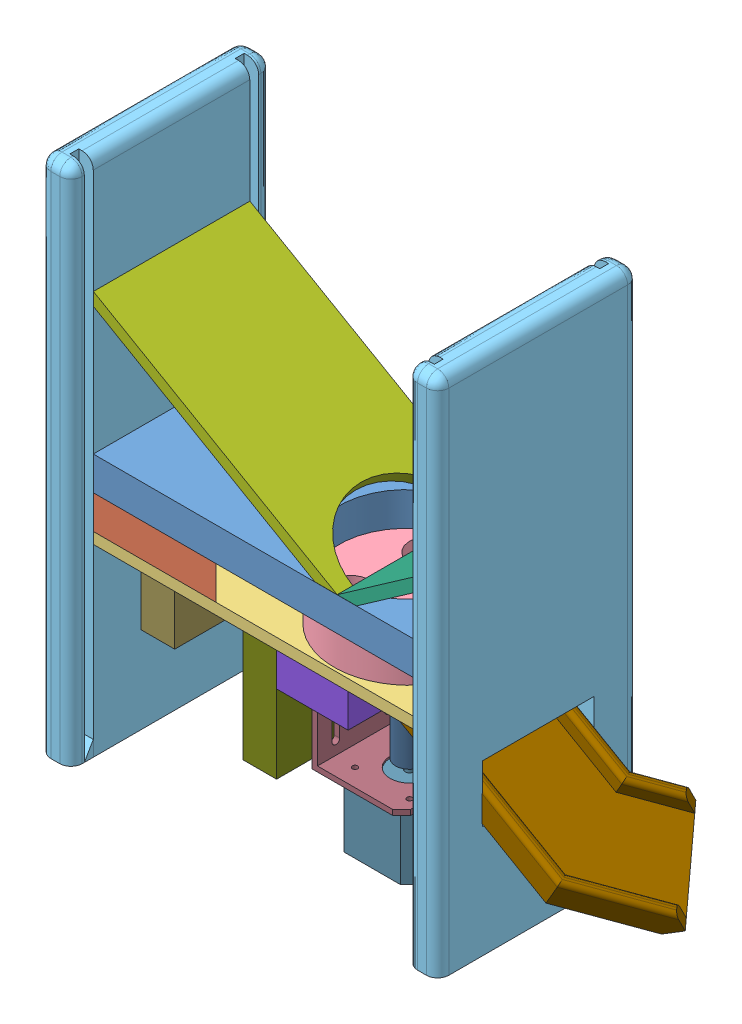
SolidWorks assembly MAIN, configuration Default. Lengths in mm.
Overall size (310.97 295.28 114.36).
20 component instances, 18 part files, 56 mates.
Components (placement in the parent):
- CenterDrop-1: CenterDrop [Default] at (73.1589 98.988 145.4321) size (190.5 19.05 88.9)
- Spacer-1: Spacer [Default] at (12.8339 79.938 145.4321) x (1 0 0) z (0 -1 0) size (69.85 88.9 19.05)
- ShaftPlate-1: ShaftPlate [Default] at (73.1589 67.238 145.4321) x (-1 0 0) z (0 -1 0) size (190.5 88.9 6.35)
- Indexer-1: Indexer [Default] at (113.1639 79.938 145.4321) x (0.075484 0 -0.997147) z (0 -1 0) size (85.72 85.72 19.05)
- SidePanel-1: SidePanel [Right] at (-30.9811 106.9255 145.4321) x (0 0 -1) z (1 0 0) size (114.3 295.28 17.78)
- SidePanel-2: SidePanel [Left] at (177.2989 106.9255 145.3686) x (0 0 1) z (-1 0 0) size (114.3 295.28 17.78)
- SlidePanel-1: SlidePanel [Default] at (73.1589 108.513 192.3586) size (207.01 292.1 5.08) (hidden)
- SmallAngle-1: SmallAngle [Default] at (144.222 124.1232 145.3686) x (0 0 -1) z (0.819152 0.573576 0) size (88.9 10.92 68.6)
- BigAngle-2: BigAngle [Default] at (53.2465 141.3043 145.3686) x (0 0 1) z (-0.866025 0.5 0) size (88.9 6.35 159.91)
- SlidePanel-2: SlidePanel [Default] at (73.1589 108.513 98.3786) x (-1 0 0) z (0 0 -1) size (207.01 292.1 5.08) (hidden)
- MotorBlock-1: MotorBlock [Default] at (102.3689 54.538 189.8821) size (40.64 19.05 88.9)
- Ramp-3: Ramp [Default] at (174.5346 34.7708 113.6821) x (-0.866025 0.5 0) z (0 0 -1) size (154.98 15.24 85.58)
- Shaft_extender-1: Shaft_extender [Default] at (113.1639 4.373 145.4321) x (0.406333 0 -0.913725) z (0.913725 0 0.406333) size (15.88 76.2 15.88)
- button-1: button [Default] at (-45.6794 41.838 145.4321) x (0 -0.933959 -0.357381) z (1 0 0) size (15.88 15.88 31.75)
- button_block-1: button_block [Default] at (-4.4044 16.565 145.4321) size (19.05 47.5 50.8)
- motor_bracket-1: motor_bracket [Default] at (113.1639 -3.247 145.4321) x (0 0 -1) z (1 0 0) size (51 48.26 51)
- motor-1: motor [Default] at (113.1639 -39.405 145.4321) x (0 0 -1) z (1 0 0) size (42.3 60.16 42.3)
- ramp_support-1: ramp_support [Default] at (166.8214 15.5913 151.7821) x (-1 0 0) z (0 0 -1) size (36.17 58.07 12.7)
- motor_block2-1: motor_block2 [Default] at (72.5239 0.563 145.4321) size (19.05 63.5 88.9)
- food_brush-1: food_brush [Default] at (116.3928 100.9412 146.1927) x (0 0 1) z (-1 0 0) size (63.5 12.7 0.38)
Mates (geometry in assembly coordinates):
- Coincident1: coincident: plane of CenterDrop-1 through (73.1589 89.463 145.4321) normal (0 -1 0); plane of Spacer-1 through (12.8339 89.463 145.4321) normal (0 1 0)
- Coincident2: coincident: plane of CenterDrop-1 through (-22.0911 108.513 100.9821) normal (-1 0 0); plane of Spacer-1 through (-22.0911 70.413 145.4321) normal (-1 0 0)
- Coincident3: coincident: plane of CenterDrop-1 through (-22.0911 108.513 100.9821) normal (0 0 -1); plane of Spacer-1 through (12.8339 70.413 100.9821) normal (0 0 -1)
- Coincident5: coincident: plane of Spacer-1 through (12.8339 70.413 145.4321) normal (0 -1 0); plane of ShaftPlate-1 through (73.1589 70.413 145.4321) normal (0 1 0)
- Coincident6: coincident: plane of CenterDrop-1 through (168.4089 108.513 100.9821) normal (1 0 0); plane of ShaftPlate-1 through (168.4089 64.063 100.9821) normal (1 0 0)
- Coincident7: coincident: plane of Spacer-1 through (12.8339 70.413 100.9821) normal (0 0 -1); plane of ShaftPlate-1 through (168.4089 64.063 100.9821) normal (0 0 -1)
- Coincident8: coincident: plane of ShaftPlate-1 through (73.1589 70.413 145.4321) normal (0 1 0); plane of Indexer-1 through (113.1639 70.413 145.4321) normal (0 -1 0)
- Concentric1: concentric: cylinder of ShaftPlate-1 through (113.1639 64.063 145.4321) axis (0 1 0) radius 7.9375; cylinder of Indexer-1 through (113.1639 80.573 145.4321) axis (0 -1 0) radius 7.9375
- Coincident12: coincident: plane of CenterDrop-1 through (168.4089 108.513 100.9821) normal (1 0 0); plane of SidePanel-2 through (168.4089 106.9255 145.3686) normal (-1 0 0)
- Coincident13: coincident: plane of CenterDrop-1 through (-22.0911 108.513 100.9821) normal (-1 0 0); plane of SidePanel-1 through (-22.0911 106.9255 145.4321) normal (1 0 0)
- Concentric3: concentric: cylinder of CenterDrop-1 through (155.7089 98.988 162.8946) axis (1 0 0) radius 3.175; cylinder of SidePanel-2 through (181.1089 98.988 162.8946) axis (-1 0 0) radius 3.175
- Coincident14: coincident: plane of CenterDrop-1 through (-22.0911 108.513 100.9821) normal (0 0 -1); plane of SidePanel-1 through (-22.0911 -40.712 100.9821) normal (0 0 -1)
- Parallel1: parallel: plane of ShaftPlate-1 through (168.4089 64.063 100.9821) normal (0 0 -1); plane of SidePanel-2 through (168.4089 -40.712 100.9186) normal (0 0 -1)
- Coincident19: coincident: plane of SidePanel-2 through (168.4089 -40.712 194.8986) normal (0 0 -1); plane of SlidePanel-1 through (73.1589 108.513 194.8986) normal (0 0 1)
- Coincident20: coincident: plane of SidePanel-2 through (176.6639 -40.712 194.8986) normal (-1 0 0); plane of SlidePanel-1 through (176.6639 254.563 194.8986) normal (1 0 0)
- Coincident21: coincident: plane of SidePanel-2 through (168.4089 254.563 88.2186) normal (0 1 0); plane of SlidePanel-1 through (-30.3461 254.563 194.8986) normal (0 1 0)
- Coincident23: coincident: plane of SidePanel-1 through (-22.0911 -40.712 202.5821) normal (0 -1 0); plane of SidePanel-2 through (168.4089 -40.712 88.2186) normal (0 -1 0)
- Coincident28: coincident: plane of SidePanel-2 through (168.4089 106.9255 145.3686) normal (-1 0 0); plane of SmallAngle-1 through (168.4089 124.1232 100.9186) normal (1 0 0)
- Coincident29: coincident: plane of SlidePanel-1 through (73.1589 108.513 189.8186) normal (0 0 -1); plane of SmallAngle-1 through (144.222 124.1232 189.8186) normal (0 0 1)
- Coincident35: coincident: plane of SlidePanel-1 through (73.1589 108.513 189.8186) normal (0 0 -1); plane of BigAngle-2 through (53.2465 141.3043 189.8186) normal (0 0 1)
- Coincident38: coincident: line of SmallAngle-1 through (116.3928 108.513 100.9186) axis (0 0 1); line of BigAngle-2 through (116.3928 108.513 189.8186) axis (0 0 -1)
- Coincident39: coincident: plane of CenterDrop-1 through (73.1589 108.513 145.4321) normal (0 1 0); plane of BigAngle-2 through (53.2465 108.513 189.8186) normal (0 -1 0)
- Coincident47: coincident: plane of SidePanel-2 through (168.4089 254.563 88.2186) normal (0 1 0); plane of SlidePanel-2 through (176.6639 254.563 95.8386) normal (0 1 0)
- Coincident48: coincident: plane of ShaftPlate-1 through (73.1589 64.063 145.4321) normal (0 -1 0); plane of MotorBlock-1 through (82.0489 64.063 100.9821) normal (0 1 0)
- Coincident49: coincident: plane of ShaftPlate-1 through (168.4089 64.063 189.8821) normal (0 0 1); plane of MotorBlock-1 through (102.3689 54.538 189.8821) normal (0 0 1)
- Distance1: distance = 45.72 mm: plane of SidePanel-2 through (168.4089 106.9255 145.3686) normal (-1 0 0); plane of MotorBlock-1 through (122.6889 64.063 100.9821) normal (1 0 0)
- Coincident72: coincident: plane of ShaftPlate-1 through (73.1589 64.063 145.4321) normal (0 -1 0); plane of Ramp-3 through (153.3116 64.063 101.5185) normal (0 1 0)
- Coincident74: coincident: plane of ShaftPlate-1 through (73.1589 64.063 145.4321) normal (0 -1 0); plane of Ramp-3 through (122.6889 64.063 177.038) normal (0 1 0)
- Coincident76: coincident: plane of Indexer-1 through (113.1639 80.573 145.4321) normal (0 -1 0); circle of Shaft_extender-1
- Coincident77: coincident: circle of Indexer-1; circle of Shaft_extender-1
- Concentric4: concentric: circle of SidePanel-1; circle of button-1
- Coincident79: coincident: plane of ShaftPlate-1 through (73.1589 64.063 145.4321) normal (0 -1 0); plane of button_block-1 through (-4.4044 64.063 145.4321) normal (0 1 0)
- Coincident81: coincident: plane of button-1 through (-13.9294 41.838 145.4321) normal (1 0 0); plane of button_block-1 through (-13.9294 64.063 120.0321) normal (-1 0 0)
- Width1: width: plane of ShaftPlate-1 through (168.4089 64.063 189.8821) normal (0 0 1); plane of ShaftPlate-1 through (168.4089 64.063 100.9821) normal (0 0 -1); plane of button_block-1 through (-13.9294 64.063 170.8321) normal (0 0 1); plane of button_block-1 through (-13.9294 64.063 120.0321) normal (0 0 -1)
- Parallel3: parallel: plane of MotorBlock-1 through (82.0489 64.063 100.9821) normal (-1 0 0); plane of motor_bracket-1 through (86.3389 -3.247 145.4321) normal (1 0 0)
- Parallel4: parallel: plane of MotorBlock-1 through (82.0489 45.013 100.9821) normal (0 -1 0); plane of motor_bracket-1 through (113.1639 -3.247 145.4321) normal (0 -1 0)
- Coincident85: coincident: plane of motor_bracket-1 through (113.1639 -3.247 145.4321) normal (0 -1 0); plane of motor-1 through (113.1639 -3.247 145.4321) normal (0 1 0)
- Coincident87: coincident: plane of MotorBlock-1 through (82.0489 45.013 100.9821) normal (0 -1 0); plane of motor_bracket-1 through (86.3389 45.013 165.8521) normal (0 1 0)
- Parallel6: parallel: plane of motor_bracket-1 through (86.3389 -3.247 145.4321) normal (1 0 0); plane of motor-1 through (134.3139 -3.247 161.5021) normal (1 0 0)
- Concentric7: concentric: cylinder of motor_bracket-1 through (113.1639 -0.247 145.4321) axis (0 -1 0) radius 11; cylinder of motor-1 through (113.1639 -1.247 145.4321) axis (0 -1 0) radius 11
- Concentric8: concentric: circle of Shaft_extender-1; circle of motor-1
- Parallel7: parallel: plane of SlidePanel-1 through (73.1589 108.513 194.8986) normal (0 0 1); plane of SlidePanel-2
- Coincident90: coincident: plane of SidePanel-2 through (176.6639 -40.712 95.8386) normal (-1 0 0); plane of SlidePanel-2 through (176.6639 254.563 95.8386) normal (1 0 0)
- Coincident91: coincident: plane of SidePanel-2 through (168.4089 -40.712 100.9186) normal (0 0 -1); plane of SlidePanel-2 through (73.1589 108.513 100.9186) normal (0 0 1)
- Coincident92: coincident: plane of SidePanel-2 through (168.4089 106.9255 145.3686) normal (-1 0 0); plane of ramp_support-1 through (168.4089 -3.4587 139.0821) normal (1 0 0)
- Parallel8: parallel: plane of ramp_support-1 through (168.4089 -3.4587 139.0821) normal (0 -1 0); plane of assembly through (0 0 0) normal (0 1 0)
- Coincident95: coincident: line of SidePanel-2 through (168.4089 34.6413 177.1186) axis (0 0 -1); line of ramp_support-1 through (168.4089 34.6413 139.0821) axis (0 0 1)
- Coincident96: coincident: plane of Ramp-3 through (172.9471 32.0212 177.1821) normal (-0.5 -0.866025 0); plane of ramp_support-1 through (168.4089 34.6413 139.0821) normal (0.5 0.866025 0)
- Coincident97: coincident: plane of ShaftPlate-1 through (73.1589 64.063 145.4321) normal (0 -1 0); plane of motor_block2-1 through (72.5239 64.063 145.4321) normal (0 1 0)
- Coincident98: coincident: plane of MotorBlock-1 through (82.0489 64.063 100.9821) normal (-1 0 0); plane of motor_block2-1 through (82.0489 64.063 189.8821) normal (1 0 0)
- Coincident99: coincident: plane of ShaftPlate-1 through (168.4089 64.063 100.9821) normal (0 0 -1); plane of motor_block2-1 through (62.9989 64.063 100.9821) normal (0 0 -1)
- Coincident100: coincident: plane of SmallAngle-1 through (116.3928 99.623 183.4686) normal (-1 0 0); plane of food_brush-1 through (116.3928 100.9412 146.1927) normal (1 0 0)
- Parallel11: parallel: plane of SmallAngle-1 through (116.3928 99.623 183.4686) normal (-1 0 0); line of food_brush-1 through (116.0118 107.2912 177.9427) axis (0 0 -1)
- Parallel13: parallel: plane of food_brush-1 through (116.0118 107.2912 114.4427) normal (0 1 0); plane of assembly through (0 0 0) normal (0 1 0)
- Width4: width: plane of ramp_support-1 through (166.8214 15.5913 139.0821) normal (0 0 -1); plane of ramp_support-1 through (166.8214 15.5913 151.7821) normal (0 0 1); plane of Ramp-3 through (174.5346 34.7708 177.1821) normal (0 0 1); plane of Ramp-3 through (174.5346 34.7708 113.6821) normal (0 0 -1)
- Width6: width: plane of Ramp-3 through (174.5346 34.7708 113.6821) normal (0 0 -1); plane of Ramp-3 through (174.5346 34.7708 177.1821) normal (0 0 1); plane of ShaftPlate-1 through (168.4089 64.063 189.8821) normal (0 0 1); plane of ShaftPlate-1 through (168.4089 64.063 100.9821) normal (0 0 -1)
